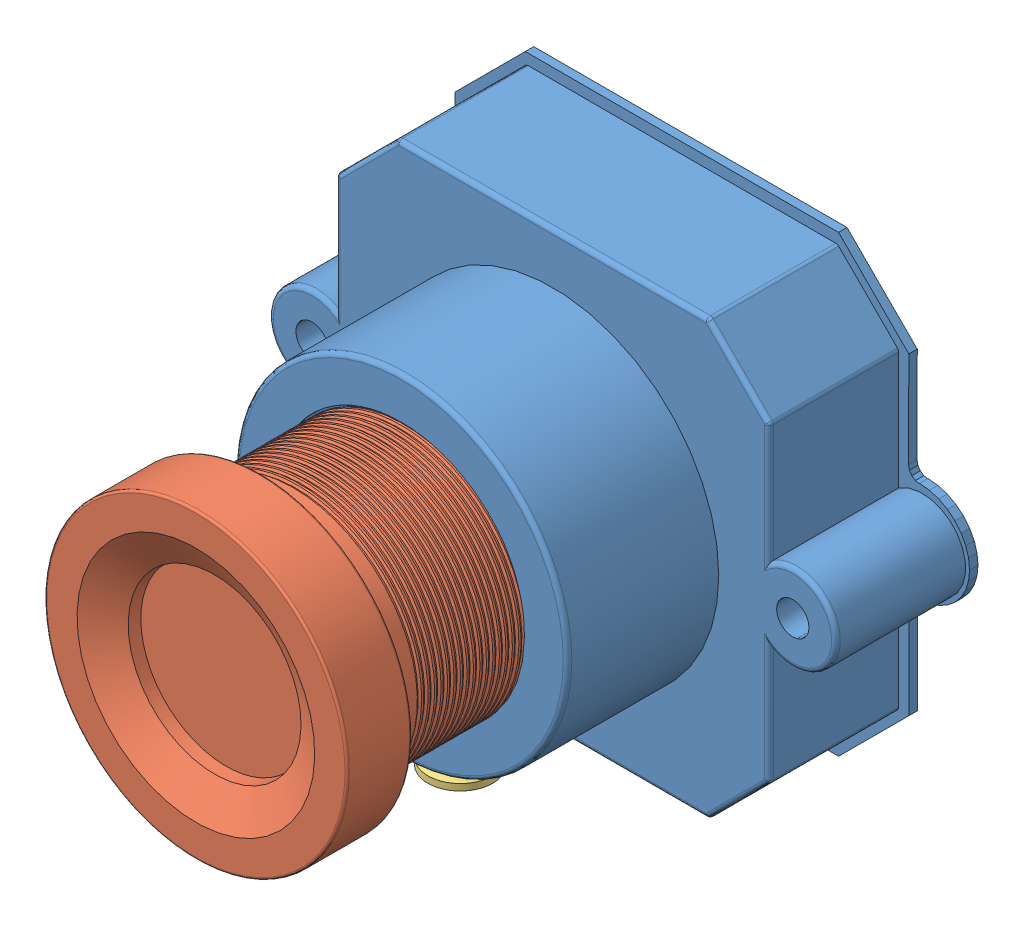
SolidWorks assembly 摄像头, configuration Default. Lengths in mm.
Overall size (26.62 21 25.09).
60 component instances, 21 part files, 3 mates.
Components (placement in the parent):
- Board摄像头-1: Board摄像头 [默认] at (0 0 -0.3912) size (26.62 21 0.39)
- Y1摄像头-1: Y1摄像头 [默认] at origin size (3.3 2.6 1.1)
  - XTAL-OSC-3225-1: XTAL-OSC-3225 [默认] at (0.2033 4.7751 -0.3912) x (1 0 0) z (0 0 -1) size (3.3 2.6 1.1)
    - User_Library-ASTX-H11_Pad-1: User_Library-ASTX-H11_Pad [默认] at origin size (3.3 2.6 0.8)
    - User_Library-ASTX-H11_Pad001-1: User_Library-ASTX-H11_Pad001 [默认] at origin size (2.8 2.4 0.24)
    - User_Library-ASTX-H11_Pad002-1: User_Library-ASTX-H11_Pad002 [默认] at origin size (2.7 2.3 0.04)
    - User_Library-ASTX-H11_ComponentPads-1: User_Library-ASTX-H11_ComponentPads [默认] at origin size (3.3 2.59 0.4)
- U2摄像头-1: U2摄像头 [默认] at origin size (2.8 2.9 1.45)
  - SOT23-5-1: SOT23-5 [默认] at (-2.517 0.4825 -0.3912) x (0 1 0) z (0 0 -1) size (2.9 2.8 1.45)
- U1摄像头-1: U1摄像头 [默认] at origin size (11.45 11.44 2.21)
  - CLCC-48-11.43x11.43mm-1: CLCC-48-11.43x11.43mm [默认] at (-0.0237 0.0119 0) x (-1 0 0) z (0 0 1) size (11.45 11.44 2.21)
- R4摄像头-1: R4摄像头 [默认] at origin size (1 0.5 0.36)
  - RES-0402-1: RES-0402 [默认] at (-5.6286 2.5399 -0.5612) x (0 -1 0) z (1 0 0) size (0.5 0.36 1)
- R3摄像头-1: R3摄像头 [默认] at origin size (1 0.5 0.36)
  - RES-0402-1: RES-0402 [默认] at (-5.6286 3.4543 -0.5612) x (0 -1 0) z (1 0 0) size (0.5 0.36 1)
- R2摄像头-1: R2摄像头 [默认] at origin size (0.5 1 0.36)
  - RES-0402-1: RES-0402 [默认] at (3.4035 2.7072 -0.5612) x (-1 0 0) z (0 -1 0) size (0.5 0.36 1)
- R1摄像头-1: R1摄像头 [默认] at origin size (1 0.5 0.36)
  - RES-0402-1: RES-0402 [默认] at (5.5524 -2.6923 -0.5612) x (0 1 0) z (-1 0 0) size (0.5 0.36 1)
- L2摄像头-1: L2摄像头 [默认] at origin size (1 0.6 0.5)
  - Chip_Inductor-0402_100505-1: Chip_Inductor-0402_100505 [默认] at (2.7686 0.7112 -0.6312) x (1 0 0) z (0 0 -1) size (1 0.6 0.5)
- L1摄像头-1: L1摄像头 [默认] at origin size (1 0.6 0.5)
  - Chip_Inductor-0402_100505-1: Chip_Inductor-0402_100505 [默认] at (2.7686 -0.1778 -0.6312) x (1 0 0) z (0 0 -1) size (1 0.6 0.5)
- D1摄像头-1: D1摄像头 [默认] at origin size (1.7 0.9 0.9)
  - LED-BLUE-0603-1: LED-BLUE-0603 [默认] at (4.4957 5.5045 -0.3912) x (0 1 0) z (0 0 -1) size (0.9 1.7 0.9)
    - User_Library-LTST-C190TBKT_Pad-1: User_Library-LTST-C190TBKT_Pad [默认] at origin size (0.9 1.7 0.28)
    - User_Library-LTST-C190TBKT_Pad005-1: User_Library-LTST-C190TBKT_Pad005 [默认] at origin size (0.35 0.15 0.31)
    - User_Library-LTST-C190TBKT_Pad001-1: User_Library-LTST-C190TBKT_Pad001 [默认] at origin size (0.9 1.7 0.01)
    - User_Library-LTST-C190TBKT_Pad004-1: User_Library-LTST-C190TBKT_Pad004 [默认] at origin size (0.35 0.15 0.31)
    - User_Library-LTST-C190TBKT_Pad003-1: User_Library-LTST-C190TBKT_Pad003 [默认] at origin size (0.8 1.7 0.02)
    - User_Library-LTST-C190TBKT_Lens-1: User_Library-LTST-C190TBKT_Lens [默认] at origin size (0.9 1.15 0.6)
- CN1摄像头-1: CN1摄像头 [默认] at origin size (13.1 6.5 2.25)
  - FPC-ZIF-SMD-Horizontal-0.5-18-1: FPC-ZIF-SMD-Horizontal-0.5-18 [默认] at (-0.0001 -9.0679 -0.3912) x (-1 0 0) z (0 -1 0) size (13.1 2.25 5.2)
  - FPC-ZIF-SMD-Horizontal-0.5-18_2-1: FPC-ZIF-SMD-Horizontal-0.5-18_2 [默认] at (-0.0001 -9.0679 -0.3912) x (-1 0 0) z (0 -1 0) size (13.1 1.2 2.95)
- C11摄像头-1: C11摄像头 [默认] at origin size (0.5 1 0.5)
  - CAP-0402-1: CAP-0402 [默认] at (-0.1015 0.0381 -0.6312) x (0 -1 0) z (1 0 0) size (1 0.5 0.5)
- C10摄像头-1: C10摄像头 [默认] at origin size (1 0.5 0.5)
  - CAP-0402-1: CAP-0402 [默认] at (-2.7305 2.6923 -0.6312) x (-1 0 0) z (0 -1 0) size (1 0.5 0.5)
- C9摄像头-1: C9摄像头 [默认] at origin size (0.5 1 0.5)
  - CAP-0402-1: CAP-0402 [默认] at (5.8421 -0.0889 -0.6312) x (0 -1 0) z (1 0 0) size (1 0.5 0.5)
- C8摄像头-1: C8摄像头 [默认] at origin size (0.5 1 0.5)
  - CAP-0402-1: CAP-0402 [默认] at (4.8261 -0.0889 -0.6312) x (0 -1 0) z (1 0 0) size (1 0.5 0.5)
- C7摄像头-1: C7摄像头 [默认] at origin size (0.5 1 0.5)
  - CAP-0402-1: CAP-0402 [默认] at (0.8383 0.0381 -0.6312) x (0 -1 0) z (1 0 0) size (1 0.5 0.5)
- C6摄像头-1: C6摄像头 [默认] at origin size (0.5 1 0.5)
  - CAP-0402-1: CAP-0402 [默认] at (-2.7687 5.4737 -0.6312) x (0 1 0) z (-1 0 0) size (1 0.5 0.5)
- C5摄像头-1: C5摄像头 [默认] at origin size (1 0.5 0.5)
  - CAP-0402-1: CAP-0402 [默认] at (5.5655 -1.5241 -0.6312) x (-1 0 0) z (0 -1 0) size (1 0.5 0.5)
- C4摄像头-1: C4摄像头 [默认] at origin size (1 0.5 0.5)
  - CAP-0402-1: CAP-0402 [默认] at (0.6731 1.5495 -0.6312) x (1 0 0) z (0 1 0) size (1 0.5 0.5)
- C3摄像头-1: C3摄像头 [默认] at origin size (0.5 1 0.5)
  - CAP-0402-1: CAP-0402 [默认] at (5.3339 2.6637 -0.6312) x (0 1 0) z (-1 0 0) size (1 0.5 0.5)
- C2摄像头-1: C2摄像头 [默认] at origin size (0.5 1 0.5)
  - CAP-0402-1: CAP-0402 [默认] at (-5.5373 -0.4445 -0.6312) x (0 1 0) z (-1 0 0) size (1 0.5 0.5)
- C1摄像头-1: C1摄像头 [默认] at origin size (0.5 1 0.5)
  - CAP-0402-1: CAP-0402 [默认] at (5.8421 2.6543 -0.6312) x (0 -1 0) z (1 0 0) size (1 0.5 0.5)
- 摄像头-1-1: 摄像头-1 [默认] at (3.1459 -0.8951 -20.4725) size (26.25 20.05 22.5)
  - 底座-1: 底座 [默认] at (-3.1409 0.8701 20.4725) size (26.25 20.05 13.15)
  - 镜头-1: 镜头 [默认] at (-3.1409 0.8701 39.9725) x (0.192959 -0.981207 0) z (0 0 -1) size (14 14 15.3)
  - 螺钉-1: 螺钉 [ISO 7047 - M1.6 x 3 - Z --- 3N] at (-3.1295 -8.8207 30.7429) x (-0.001176 0.999999 0) z (-0.196345 -0.000231 0.980535) size (3.37 3 3)
Mates (geometry in assembly coordinates):
- 重合1: coincident anti-aligned: plane of Board摄像头-1 through (-7.25 -10.5 0) normal (0 0 1); plane of 摄像头-1-1/底座-1 through (-11.12 -0.075 0) normal (0 0 -1)
- 距离2: distance = 0.47 mm aligned: plane of Board摄像头-1 through (10.5 -7.25 -0.3912) normal (1 0 0); plane of 摄像头-1-1/底座-1 through (10.03 -1.6953 6) normal (1 0 0)
- 距离1: distance = 0.45 mm aligned: plane of 摄像头-1-1/底座-1 through (-7.1916 -10.05 6) normal (0 -1 0); plane of Board摄像头-1 through (-7.25 -10.5 -0.3912) normal (0 -1 0)
